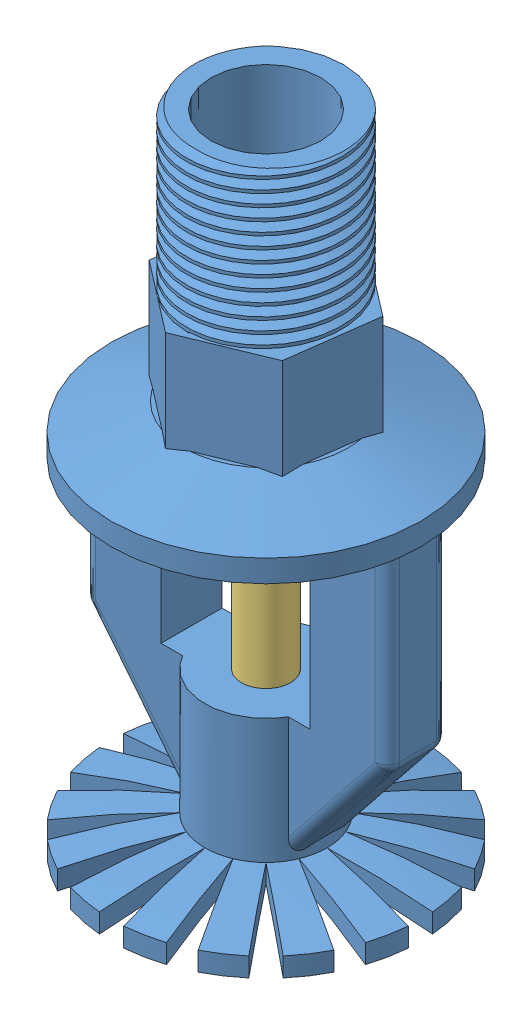
SolidWorks assembly sprayer, configuration Default. Lengths in mm.
Overall size (25.4 53.15 25.4).
3 component instances, 3 part files, 5 mates.
Components (placement in the parent):
- body_sprayer-1: body_sprayer [Default] at (18.1164 37.3176 44.3194) size (25.4 53.15 25.4)
- top_sprayer-1: top_sprayer [Default] at (18.1164 25.8537 44.3194) x (0 -1 0) z (0 0 1) size (2 10.37 10.37)
- liquid_sprayer-1: liquid_sprayer [Default] at (18.1164 17.0837 44.3194) x (0.788396 0 -0.615168) z (0.615168 0 0.788396) size (4 17.04 4)
Mates (geometry in assembly coordinates):
- Coincident1: coincident aligned: circle of body_sprayer-1; cylinder of top_sprayer-1 through (18.1164 25.8537 44.3194) axis (0 1 0) radius 436.3323
- Concentric1: concentric anti-aligned: circle of Sprinkler-1; circle of top-1
- Parallel1: parallel aligned: plane of Sprinkler-1 through (18.1164 25.3176 44.3194) normal (0 -1 0); plane of top-1 through (18.1164 23.8537 44.3194) normal (0 -1 0)
- Concentric2: concentric: sphere of top-1; sphere of Liquid-1
- Concentric3: concentric aligned: circle of top-1; circle of Liquid-1
